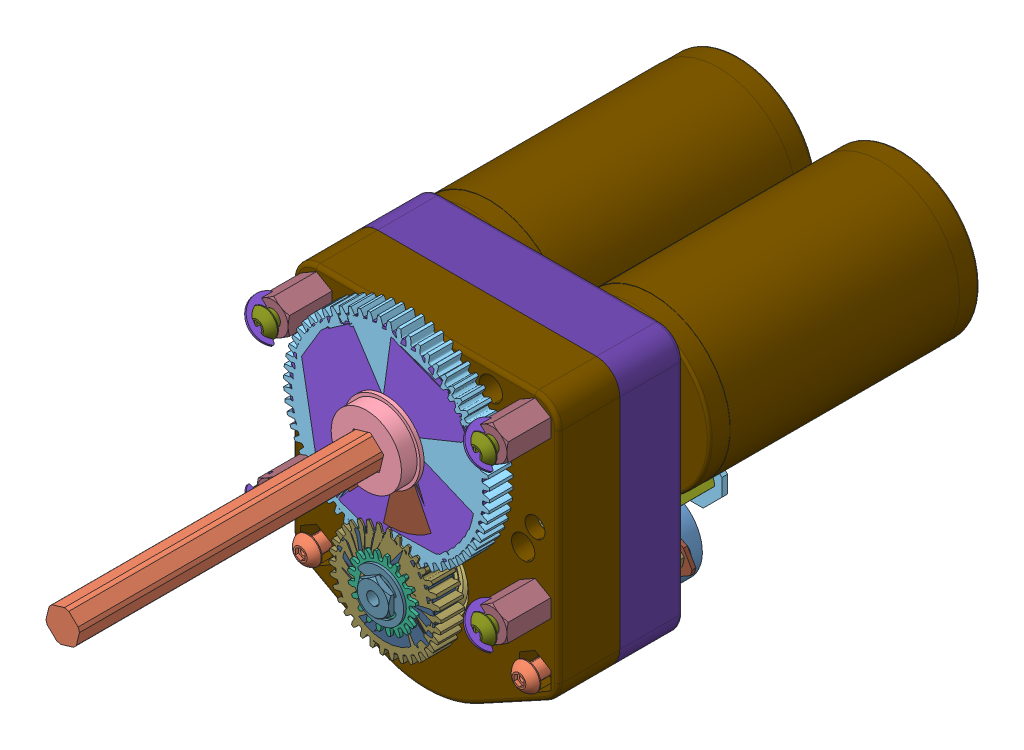
SolidWorks assembly Chassis Gearbox 2016, configuration Default. Lengths in mm.
Overall size (144.51 156.19 312.65).
112 component instances, 62 part files, 0 mates.
Components (placement in the parent):
- 217-2733-001 Rev2-1: 217-2733-001 Rev2 [Default] at (0 53.4162 12.0523) x (0 0 1) z (0.878299 0.478111 0) size (7.11 24.61 24.61)
- 217-2733-001 Rev2-2: 217-2733-001 Rev2 [Default] at (0 53.4162 -17.6911) x (0 0 -1) z (0.971421 0.237365 0) size (7.11 24.61 24.61)
- 217-2731-001 Rev2-1: 217-2731-001 Rev2 [Default] at (0 0 -25.6286) x (0.99998 -0.006249 0) z (-0.006249 -0.99998 0) size (31.12 7.94 31.12)
- 217-2789-001 Rev2-1: 217-2789-001 Rev2 [Default] at (0 0 17.6784) x (0 0 -1) z (0.997427 0.071687 0) size (11.1 38.4 38.4)
- 217-2788-001 Rev3_57155K375-1: 217-2788-001 Rev3_57155K375 [Default] at (0 0 -46.8376) x (0.743593 0.668633 0) z (0 0 1) size (9.53 9.53 3.17)
- 217-2428-012 Rev2-1: 217-2428-012 Rev2 [Default] at (0 0 -66.0019) size (63.5 22.23 2.29)
- 217-2428-027 Rev1_97414A630-1: 217-2428-027 Rev1_97414A630 [Default] at (0 0 -48.7426) x (0 0 -1) z (-0.538463 -0.842649 0) size (7.37 7.12 7.9)
- 217-2428-005 Rev1-1: 217-2428-005 Rev1 [Default] at (25.4 0 -44.6659) x (-0.968533 0.248884 0) z (0.248884 0.968533 0) size (7.33 38.98 6.35)
- 217-2428-005 Rev1-2: 217-2428-005 Rev1 [Default] at (-25.4 0 -44.6659) x (0.661665 -0.7498 0) z (-0.7498 -0.661665 0) size (7.33 38.98 6.35)
- SCREW-832-0375-1: SCREW-832-0375 [Default] at (25.4 0 -68.2117) x (0 0 1) z (-0.875404 0.483392 0) size (11.73 7.92 7.92)
- SCREW-832-0375-2: SCREW-832-0375 [Default] at (-25.4 0 -68.2117) x (0 0 1) z (-0.875404 0.483392 0) size (11.73 7.92 7.92)
- SCREW-832-0375-3: SCREW-832-0375 [Default] at (25.4 0 -20.2311) x (0 0 -1) z (1 0 0) size (11.73 7.92 7.92)
- SCREW-832-0375-4: SCREW-832-0375 [Default] at (-25.4 0 -20.2311) x (0 0 -1) z (0.999351 0.036025 0) size (11.73 7.92 7.92)
- SBS1_SBS-0632-0250-1: SBS1_SBS-0632-0250 [Default] at (15.494 0 -61.8617) x (0 0 -1) z (0.854303 -0.519775 0) size (8.57 6.68 6.65)
- SBS1_SBS-0632-0250-2: SBS1_SBS-0632-0250 [Default] at (-15.494 0 -61.8617) x (0 0 -1) z (0.854303 -0.519775 0) size (8.57 6.68 6.65)
- 217-2428-016 Rev3_Spur01-1: 217-2428-016 Rev3_Spur01 [Default] at (0 0 -29.2807) x (0.982225 0.187706 0) z (0 0 1) size (40.67 40.74 13.32)
- 217-2428-019 Rev1-1: 217-2428-019 Rev1 [Default] at (12.7 -21.997 -46.2407) x (0.866025 0.5 0) z (0 0 1) size (50.8 19.05 1.57)
- 217-2428-006 Rev1-1: 217-2428-006 Rev1 [Default] at (32.079 -14.2875 -35.1409) x (-0.95139 -0.30799 0) z (-0.30799 0.95139 0) size (7.33 19.93 6.35)
- 217-2428-006 Rev1-2: 217-2428-006 Rev1 [Default] at (-3.6662 -34.925 -35.1409) x (-0.054239 0.998528 0) z (0.998528 0.054239 0) size (7.33 19.93 6.35)
- SCREW-832-0375-5: SCREW-832-0375 [Default] at (32.079 -14.2875 -20.2311) x (0 0 -1) z (0.980613 0.195955 0) size (11.73 7.92 7.92)
- SCREW-832-0375-6: SCREW-832-0375 [Default] at (-3.6662 -34.925 -20.2311) x (0 0 -1) z (-0.826375 -0.56312 0) size (11.73 7.92 7.92)
- SCREW-832-0375-7: SCREW-832-0375 [Default] at (-3.6662 -34.925 -48.4505) x (0 0 1) z (0.948865 0.315681 0) size (11.73 7.92 7.92)
- SCREW-832-0375-8: SCREW-832-0375 [Default] at (32.079 -14.2875 -48.4505) x (0 0 1) z (-0.875404 0.483392 0) size (11.73 7.92 7.92)
- 217-2428-017 Rev2-1: 217-2428-017 Rev2 [Default] at (12.7 -21.997 -29.2807) x (0.976331 0.216282 0) z (0 0 1) size (14.73 14.73 7.37)
- SBS1_SBS1032-0500ZC-1: SBS1_SBS1032-0500ZC [Default] at (-39.6321 27.2942 -19.8755) x (0 0 -1) z (0.878202 0.478289 0) size (15.78 9.29 9.24)
- SBS1_SBS1032-0500ZC-2: SBS1_SBS1032-0500ZC [Default] at (-26.4841 76.3632 -19.8755) x (0 0 -1) z (0.751237 -0.660033 0) size (15.78 9.29 9.24)
- 217-2614-001_12t-1: 217-2614-001_12t [Default] at (-33.0581 51.8287 -4.1095) x (-0.258819 -0.965926 0) z (0 0 1) size (18.29 18.29 19)
- 217-2761-001 rev1-1: 217-2761-001 rev1 [Default] at (-29.3876 50.8452 -9.5159) x (0.258819 0.965926 0) z (0 0 1) size (2 2 20)
- SBS1_SBS1032-0500ZC-3: SBS1_SBS1032-0500ZC [Default] at (39.6321 27.2942 -19.8755) x (0 0 -1) z (0.618676 -0.785646 0) size (15.78 9.29 9.24)
- SBS1_SBS1032-0500ZC-4: SBS1_SBS1032-0500ZC [Default] at (26.4841 76.3632 -19.8755) x (0 0 -1) z (0.996655 0.081722 0) size (15.78 9.29 9.24)
- 217-2761-001 rev1-2: 217-2761-001 rev1 [Default] at (29.3876 50.8452 -9.5159) x (-0.258819 0.965926 0) z (0 0 1) size (2 2 20)
- 217-2614-001_12t-2: 217-2614-001_12t [Default] at (33.0581 51.8287 -4.1095) x (-0.258819 0.965926 0) z (0 0 1) size (18.29 18.29 19)
- 217-2428-001 Rev1-1: 217-2428-001 Rev1 [Default] at (0 53.4162 -25.6159) size (107.95 127.51 28.8)
- 217-2428-002 Rev2-1: 217-2428-002 Rev2 [Default] at (0 53.4162 24.9301) x (-1 0 0) z (0 0 -1) size (107.95 127.51 28.11)
- 217-2703-001-1: 217-2703-001 [Default] at (0 53.4162 4.5339) x (-0.958428 0.285334 0) z (0 0 1) size (33.29 33.29 12.65)
- 217-2707-001_40t-1: 217-2707-001_40t [Default] at (0 53.4162 -8.1661) x (0.726321 0.687356 0) z (0 0 1) size (53.62 53.62 12.65)
- SBS1_SBS0832-1750SS-1: SBS1_SBS0832-1750SS [Default] at (-44.45 36.7075 21.4249) x (0 0 -1) z (0.052618 -0.998615 0) size (47.11 8.02 7.99)
- SBS1_SBS0832-1750SS-2: SBS1_SBS0832-1750SS [Default] at (44.45 36.7075 21.4249) x (0 0 -1) z (0.699378 -0.714752 0) size (47.11 8.02 7.99)
- Nylock Nut_NNY2520-ZC-1: Nylock Nut_NNY2520-ZC [Default] at (44.45 -14.0925 -17.7546) x (0 1 0) z (0 0 -1) size (12.85 11.89 7.62)
- Nylock Nut_NNY2520-ZC-2: Nylock Nut_NNY2520-ZC [Default] at (44.45 74.8075 -17.7546) x (0 1 0) z (0 0 -1) size (12.85 11.89 7.62)
- 217-2428-004 Rev3-1: 217-2428-004 Rev3 [Default] at (0 53.4162 -2.8448) x (0.97269 0.232108 0) z (0 0 1) size (11 9.53 43.92)
- 217-2428-021 Rev1-1: 217-2428-021 Rev1 [Default] at (0 53.4162 -16.1036) x (0.999182 0.040427 0) z (0 0 1) size (15.88 15.88 3.17)
- 217-2428-029 Rev1-1: 217-2428-029 Rev1 [Default] at (0 53.4162 11.4173) size (15.88 15.88 1.12)
- Nylock 8-32-1: Nylock 8-32 [Default] at (44.45 36.7075 -19.2659) x (0.254216 0.967147 0) z (-0.967147 0.254216 0) size (10.2 4.9 8.12)
- Nylock 8-32-2: Nylock 8-32 [Default] at (-44.45 36.7075 -19.2659) x (0.948441 0.316954 0) z (-0.316954 0.948441 0) size (10.2 4.9 8.12)
- 217-2793-001 Rev1-1: 217-2793-001 Rev1 [Default] at (0 0 -25.5778) x (0 -1 0) z (0 0 1) size (82.39 82.39 97.02)
  - 217-2428-008 Rev2-1: 217-2428-008 Rev2 [Default] at (0 0 10.2679) size (31.75 31.75 1.59)
  - 217-2428-028 Rev1_97633A250-1: 217-2428-028 Rev1_97633A250 [Default] at (0 0 37.1221) x (0 0 1) z (0.9357 -0.352797 0) size (1.07 23.39 21.18)
  - 217-2709-101 Rev1-1: 217-2709-101 Rev1 [Default] at (0 0 20.7137) x (-0.998987 -0.044993 0) z (0 0 -1) size (58.74 58.74 12.7)
    - 217-2428-022 Rev1-1: 217-2428-022 Rev1 [Default] at origin size (28.57 28.57 6.1)
    - 217-2709-001_44t Steel-1: 217-2709-001_44t Steel [Default] at (0 0 3.302) size (58.74 58.74 11.11)
  - 217-2713-101 Rev1-1: 217-2713-101 Rev1 [Default] at (0 0 30.1117) x (-0.998987 -0.044993 0) z (0 0 -1) size (78.91 78.91 12.7)
    - 217-2428-022 Rev1-1: 217-2428-022 Rev1 [Default] at (0 0 -3.302) size (28.57 28.57 6.1)
    - 217-2713-001_60t Steel-1: 217-2713-001_60t Steel [Default] at origin size (78.91 78.91 11.11)
  - 217-2791-001 Rev2-1: 217-2791-001 Rev2 [Default] x (-1 0 0) z (0 0 1) size (22.23 22.23 97.02)
    - 217-2791-002 Rev2-1: 217-2791-002 Rev2 [Default] at (0 0 53.467) x (0 -1 0) z (0 0 1) size (12.7 16.13 36.96)
    - 217-2790-003 Rev2-1: 217-2790-003 Rev2 [Default] at origin size (22.23 22.23 55.94)
    - 217-2790-004 Rev2-1: 217-2790-004 Rev2 [Default] at (0 0 14.5022) x (0.877055 0.48039 0) z (0 0 1) size (11.68 11.68 55)
  - 217-2428-007 Rev1-1: 217-2428-007 Rev1 [Default] at (6.275 0 14.2494) x (0.477673 -0.652226 -0.588582) z (0.408838 -0.427964 0.806039) size (6.35 6.35 6.35)
  - 217-2428-007 Rev1-2: 217-2428-007 Rev1 [Default] at (6.275 0 26.9494) x (-0.162331 -0.978398 0.128005) z (0.857281 -0.204076 -0.472676) size (6.35 6.35 6.35)
  - 217-2428-007 Rev1-3: 217-2428-007 Rev1 [Default] at (-3.1375 5.4343 14.2494) x (0.326008 0.73979 -0.588582) z (0.166208 0.568046 0.806039) size (6.35 6.35 6.35)
  - 217-2428-007 Rev1-4: 217-2428-007 Rev1 [Default] at (-3.1375 -5.4343 14.2494) x (-0.803681 -0.087564 -0.588582) z (-0.575047 -0.140083 0.806039) size (6.35 6.35 6.35)
  - 217-2428-007 Rev1-5: 217-2428-007 Rev1 [Default] at (-3.1375 5.4343 26.9494) x (0.928483 0.348617 0.128005) z (-0.251905 0.844465 -0.472676) size (6.35 6.35 6.35)
  - 217-2428-007 Rev1-6: 217-2428-007 Rev1 [Default] at (-3.1375 -5.4343 26.9494) x (-0.766153 0.629782 0.128005) z (-0.605376 -0.640389 -0.472676) size (6.35 6.35 6.35)
- 217-2000-1: 217-2000 [Default] at (33.0581 51.8287 -25.6159) x (0 0 -1) z (0.965926 0.258819 0) size (150.2 64.01 64.01)
- 217-2000-2: 217-2000 [Default] at (-33.0581 51.8287 -25.6159) x (0 0 -1) z (-0.965926 0.258819 0) size (150.2 64.01 64.01)
- Grahill Encoder-1: Grahill Encoder [Default] at (12.7 -21.997 -41.7957) x (0.902286 -0.431138 0) z (0.431138 0.902286 0) size (31.75 31.12 31.75)
- 217-2617-003 Rev2-1: 217-2617-003 Rev2 [Default] at (0 53.4162 96.2376) x (-0.959408 -0.282023 0) z (0 0 1) size (13.74 12.7 152.4)
- 217-3109-001 Rev1-1: 217-3109-001 Rev1 [Default] at (0 53.4162 23.5648) x (0 0 -1) z (-0.999944 0.010604 0) size (7.94 28.57 28.57)
- 217-2734-001 Rev3-1: 217-2734-001 Rev3 [Default] at (0 53.4162 49.0601) x (0.235465 0.971883 0) z (-0.971883 0.235465 0) size (31.12 7.94 31.12)
- 217-2715-002 Rev1_64t-1: 217-2715-002 Rev1_64t [Default] at (0 53.4162 36.0366) x (-0.68986 -0.723943 0) z (0 0 1) size (84.3 84.3 12.65)
- 217-2702-001_20t-1: 217-2702-001_20t [Default] at (0 0 36.6903) x (0.625762 -0.780014 0) z (0 0 1) size (28.2 28.2 12.65)
- 217-2704-001_24-1: 217-2704-001_24 [Default] at (0 0 35.0841) x (0.993482 -0.113989 0) z (0 0 1) size (33.29 33.29 12.65)
- 217-2714-002 Rev1_60t-1: 217-2714-002 Rev1_60t [Default] at (0 53.4162 36.0366) x (-0.68986 -0.723943 0) z (0 0 1) size (78.95 78.95 12.65)
- 217-3221-002 Rev1-1: 217-3221-002 Rev1 [Default] at (0 53.4162 36.0239) x (-0.68986 -0.723943 0) z (0 0 1) size (71.39 71.45 12.62)
- 217-2705-001_30t-1: 217-2705-001_30t [Default] at (0 0 36.6903) size (41.01 41.12 12.65)
- 217-2712-002 Rev1_50t-1: 217-2712-002 Rev1_50t [Default] at (0 53.4162 36.0366) x (0.971883 -0.235465 0) z (0 0 1) size (66.7 66.76 12.65)
- 217-2706-001_34t-1: 217-2706-001_34t [Default] at (0 0 36.6903) x (0.5 0.866025 0) z (0 0 1) size (46.46 46.56 12.65)
- 217-2617-002 Rev1_91780A359-1: 217-2617-002 Rev1_91780A359 [Default] at (-44.45 74.8075 30.0101) size (12.7 14.66 25.4)
- 217-2617-002 Rev1_91780A359-2: 217-2617-002 Rev1_91780A359 [Default] at (44.45 74.8075 30.0101) x (-0.5 -0.866025 0) z (0 0 -1) size (12.7 14.66 25.4)
- 217-2617-002 Rev1_91780A359-3: 217-2617-002 Rev1_91780A359 [Default] at (-44.45 11.3075 30.0101) size (12.7 14.66 25.4)
- 217-2617-002 Rev1_91780A359-4: 217-2617-002 Rev1_91780A359 [Default] at (44.45 11.3075 30.0101) size (12.7 14.66 25.4)
- 217-2617-004 Rev1_97431A340_grv-1: 217-2617-004 Rev1_97431A340_grv [Default] at (0 0 43.5483) x (0 0 1) z (-1 0 0) size (1.07 20.42 18.58)
- 217-2617-004 Rev1_97431A340_grv-2: 217-2617-004 Rev1_97431A340_grv [Default] at (0 53.4162 29.1786) x (0 0 1) z (-1 0 0) size (1.07 20.42 18.58)
- SBS1_SBS2520-1750-1: SBS1_SBS2520-1750 [Default] at (44.45 11.3075 -18.1737) x (0 0 1) z (-0.961255 0.27566 0) size (48.48 11.22 11.17)
- SBS1_SBS2520-1750-2: SBS1_SBS2520-1750 [Default] at (44.45 74.8075 -18.1737) x (0 0 1) z (-0.983108 -0.183029 0) size (48.48 11.22 11.17)
- SBS1_SBS2520-1750-3: SBS1_SBS2520-1750 [Default] at (-44.45 74.8075 -18.1737) x (0 0 1) z (-0.878539 0.47767 0) size (48.48 11.22 11.17)
- SBS1_SBS2520-1750-4: SBS1_SBS2520-1750 [Default] at (-44.45 11.3075 -18.1737) x (0 0 1) z (-0.805318 -0.592843 0) size (48.48 11.22 11.17)
- SBS1_SBS2520-0625ZC-1: SBS1_SBS2520-0625ZC [Default] at (-44.45 74.8075 49.2379) x (0 0 -1) z (0.963378 0.268146 0) size (19.57 11.22 11.17)
- SBS1_SBS2520-0625ZC-2: SBS1_SBS2520-0625ZC [Default] at (-44.45 11.3075 49.2379) x (0 0 -1) z (-0.232142 -0.972682 0) size (19.57 11.22 11.17)
- SBS1_SBS2520-0625ZC-3: SBS1_SBS2520-0625ZC [Default] at (44.45 74.8075 49.2379) x (0 0 -1) z (-0.560912 -0.827875 0) size (19.57 11.22 11.17)
- SBS1_SBS2520-0625ZC-4: SBS1_SBS2520-0625ZC [Default] at (44.45 11.3075 49.2379) x (0 0 -1) z (0.367215 0.930136 0) size (19.57 11.22 11.17)
- 217-2778-001 Rev2_NCQ8A075-050M-1: 217-2778-001 Rev2_NCQ8A075-050M [Default] at (0 0 -79.4639) x (0.71017 0.704031 0) z (0 0 1) size (31.75 33.34 39.88)
  - 217-2778-002_075A-1: 217-2778-002_075A [Default] at origin size (31.75 33.34 26.92)
  - 217-2778-003_075M-1: 217-2778-003_075M [Default] at (0 0 -8.85) x (0.156073 -0.987746 0) z (0 0 1) size (18.95 18.95 35.27)
  - 217-2778-004_075-1: 217-2778-004_075 [Default] at (0 0 10.362) size (21 20.74 0.97)
- Nylock Nut_NNY2520-ZC-3: Nylock Nut_NNY2520-ZC [Default] at (-44.45 -14.0925 -17.7546) x (0 1 0) z (0 0 -1) size (12.85 11.89 7.62)
- SBS1_SBS2520-2000ZC-1: SBS1_SBS2520-2000ZC [Default] at (-44.45 -14.0925 31.4579) x (0 0 -1) z (1 0 0) size (54.83 11.22 11.17)
- SBS1_SBS2520-2000ZC-2: SBS1_SBS2520-2000ZC [Default] at (44.45 -14.0925 31.4579) x (0 0 -1) z (1 0 0) size (54.83 11.22 11.17)
- 217-2428-032 Rev1-1: 217-2428-032 Rev1 [Default] at (0 0 -53.8734) x (0.806241 -0.591587 0) z (0 0 -1) size (18.09 11.02 22.68)
- 217-2428-032 Rev1-2: 217-2428-032 Rev1 [Default] at (0 0 -53.8734) x (-0.806241 0.591587 0) z (0 0 -1) size (18.09 11.02 22.68)
- 217-2778-NCQ8A075-050M_1032_Nut_90545A111-1: 217-2778-NCQ8A075-050M_1032_Nut_90545A111 [Default] at (0 0 -56.2229) x (-0.806241 0.591587 0) z (0 0 -1) size (9.53 11 3.39)
- 91251A107_91251A107-1: 91251A107_91251A107 [Default] at (2.342 -7.8426 -50.6984) x (-0.572568 0.420127 0.704031) z (-0.591587 -0.806241 0) size (4.65 4.65 10.79)
- 91251A107_91251A107-2: 91251A107_91251A107 [Default] at (-2.342 7.8426 -50.6984) x (-0.768326 0.563766 -0.303056) z (0.591587 0.806241 0) size (4.65 4.65 10.79)
- 217-2428-023 Rev1_9714K3-1: 217-2428-023 Rev1_9714K3 [Default] at (0 0 10.8839) x (0.147022 0.989133 0) z (0.989133 -0.147022 0) size (26.82 4.09 28.39)
- 217-2428-027 Rev1_97414A630-2: 217-2428-027 Rev1_97414A630 [Default] at (0 0 -44.9326) x (0 0 -1) z (0.823209 -0.567739 0) size (7.37 7.12 7.9)
- SCREW-632-0250-1: SCREW-632-0250 [Default] at (-15.494 0 -61.8617) x (0 0 -1) z (1 0 0) size (8.2 6.59 6.59)
- SCREW-632-0250-2: SCREW-632-0250 [Default] at (15.494 0 -61.8617) x (0 0 -1) z (1 0 0) size (8.2 6.59 6.59)
- 97431A320_97431A320-1: 97431A320_97431A320 [Default] at (-44.45 11.3075 43.3197) x (-0.67505 -0.737772 0) z (-0.737772 0.67505 0) size (0.89 16.76 15.36)
- 97431A320_97431A320-2: 97431A320_97431A320 [Default] at (44.45 11.3075 43.3197) x (0.67505 0.737772 0) z (0.737772 -0.67505 0) size (0.89 16.76 15.36)
- 97431A320_97431A320-3: 97431A320_97431A320 [Default] at (44.45 74.8075 43.3197) x (0.67505 0.737772 0) z (0.737772 -0.67505 0) size (0.89 16.76 15.36)
- 97431A320_97431A320-4: 97431A320_97431A320 [Default] at (-44.45 74.8075 43.3197) x (0.67505 0.737772 0) z (0.737772 -0.67505 0) size (0.89 16.76 15.36)
